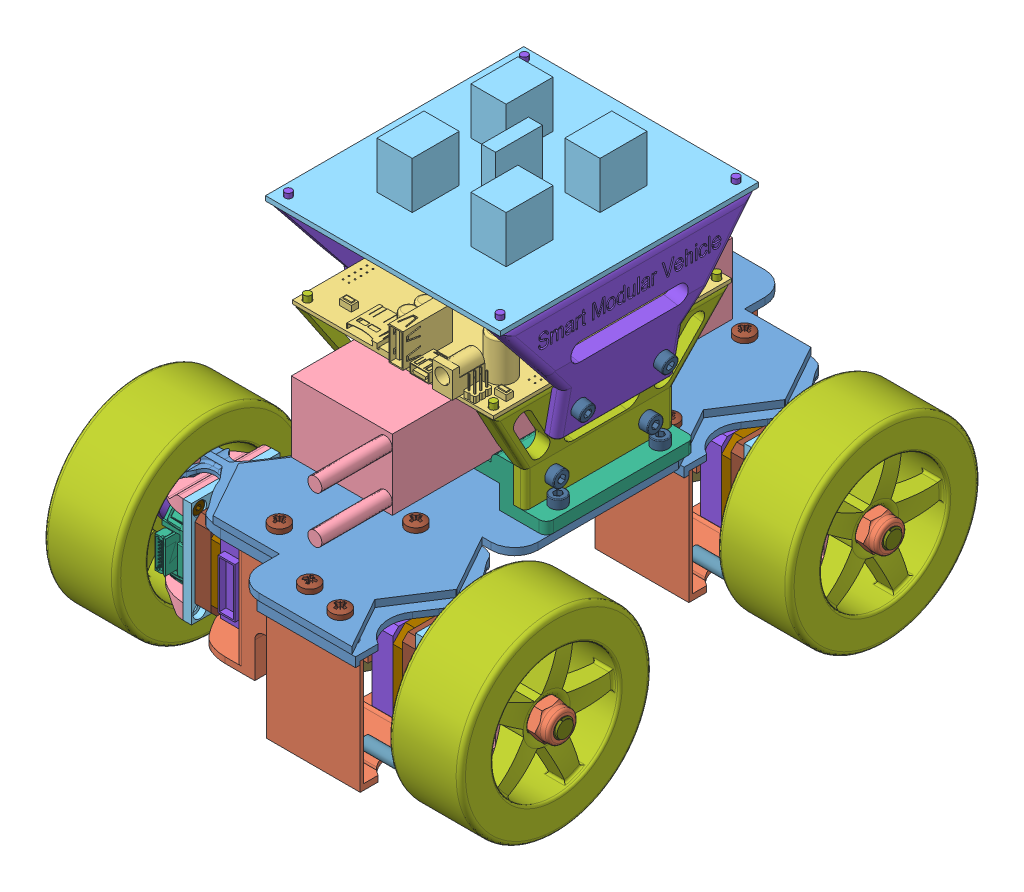
SolidWorks assembly Test chassis, configuration Default. Lengths in mm.
Overall size (185.37 190.89 245.78).
162 component instances, 31 part files, 60 mates.
Components (placement in the parent):
- Chassis-1: Chassis [Default] at origin size (92.7 3 227)
- Module Assembly-1: Module Assembly [Default] at (-66.5 -27.5 -66.5) x (0 0 1) z (-1 0 0) size (105.78 105.78 97.81)
  - Housing-1: Housing [Default] at origin size (64.25 48.5 67.91)
  - Lager 12x8-1: Lager 12x8 [Default] at (0 -18.25 0.75) x (-0.914388 0 0.40484) z (-0.40484 0 -0.914388) size (12 3.5 12)
  - Fusee-1: Fusee [Default] at (0 2 0.75) size (49.04 45 20.5)
  - Fusee base-1: Fusee base [Default] at (0 2 -15.25) x (-1 0 0) z (0 -1 0) size (37.62 3.5 44.8)
  - amt112s-v-1: amt112s-v [Défaut] at (0 2 -12.48) x (0 1 0) z (0 0 1) size (28.68 37.25 10.4)
  - Wheel-1: Wheel [Default] at (0 2 -8.55) x (0.929787 0.368098 0) z (0.368098 -0.929787 0) size (81.5 31 81.5)
  - Ensamblaje_Nema14-1: Ensamblaje_Nema14 [Predeterminado] at (4.764 -15.5 -30.1157) x (-1 0 0) z (0 1 0) size (37.8 40 35)
    - nema14_base-1: nema14_base [Predeterminado] at (-12.736 -8.6343 35) size (37.8 9 35)
    - nema14_centro-1: nema14_centro [Predeterminado] at (-12.736 0.3657 35) size (35 4 35)
    - nema14_eje-1: nema14_eje [Predeterminado] at (4.764 -6.6343 17.5) x (0 1 0) z (-0.939004 0 0.343907) size (38 5 5)
    - nema14_techo-1: nema14_techo [Predeterminado] at (-12.736 4.3657 35) size (35 9 35)
  - TowerPro-SG90-Montaj-1: TowerPro-SG90-Montaj [Default] at (-25.7048 26.288 -66.0832) x (0 0 1) z (1 0 0) size (11.5 29.2 32.5) (flexible)
    - TowerPro-SG90-Body-1: TowerPro-SG90-Body [Default] at (13.6721 7.288 30.7048) size (11.5 26 32.5) (hidden)
    - ServoFinalGear-1: ServoFinalGear [Default] at (13.6721 33.288 25.7048) x (0.607544 0 -0.794286) z (0.794286 0 0.607544) size (4.64 3.2 4.64) (hidden)
  - Servo control dual control horn-1: Servo control dual control horn [Default] at (0 -7.5 -52.4111) x (0.891007 0 0.45399) z (0.45399 0 -0.891007) size (37.9 4.5 7.8)
  - Ball joint assy-1: Ball joint assy [Default] at (-26.7302 -5 -12.8697) x (-0.874356 0 0.485286) z (0.485286 0 0.874356) size (15.43 16.21 22.24) (flexible)
    - Ball-1: Ball [Default] at origin size (5.5 15.11 5.5)
    - Joint-1: Joint [Default] at (-3.8823 13.66 -6.9948) x (0.874356 0 -0.485286) z (0 -1 0) size (5.1 22.6 5.1)
  - Ball joint assy-2: Ball joint assy [Default] at (-26.7302 -5 -66.0308) x (-0.846813 0 0.531891) z (0.531891 0 0.846813) size (16.34 16.21 21.85) (flexible)
    - Ball-1: Ball [Default] at origin size (5.5 15.11 5.5)
    - Joint-1: Joint [Default] at (4.2551 13.66 6.7745) x (-0.846813 0 0.531891) z (0 -1 0) size (5.1 22.6 5.1)
  - Steering rod-1: Steering rod [Default] at (-26.7302 -18.66 -18.4608) x (-0.014502 0.999895 0) z (-0.999895 -0.014502 0) size (3 28.27 3)
  - Wheel adapter-1: Wheel adapter [Default] at (0 2 -13.8175) x (0.291296 -0.956633 0) z (-0.956633 -0.291296 0) size (8.34 40 8.37)
  - Wheel spacer-1: Wheel spacer [Default] at (0 2 12.25) x (0.368098 -0.929787 0) z (0.929787 0.368098 0) size (13.86 8 12)
  - screw_din_7984-m3x5-8_8-1: screw_din_7984-m3x5-8_8 [Default] at (15.31 20.9 -16.25) x (0.933505 0.358563 0) z (0 0 -1) size (5.5 5.5 7)
  - Housing lid-1: Housing lid [Default] at (0 4 0) x (-1 0 0) z (0 0 1) size (68.25 9.28 69.91)
  - Lager 12x8-3: Lager 12x8 [Default] at (0 22.25 0.75) x (-0.914388 0 0.40484) z (0.40484 0 0.914388) size (12 3.5 12) (hidden)
  - M8 nut-1: M8 nut [Default] at (0 2 16.6825) x (-0.817347 -0.576146 0) z (0 0 1) size (13 16.06 8.5)
  - screw_din_7984-m3x5-8_8-2: screw_din_7984-m3x5-8_8 [Default] at (15.31 -16.9 -16.25) x (-0.933505 0.358563 0) z (0 0 -1) size (5.5 5.5 7) (hidden)
  - screw_din_7984-m3x5-8_8-3: screw_din_7984-m3x5-8_8 [Default] at (-15.31 20.9 -16.25) x (0.933505 -0.358563 0) z (0 0 -1) size (5.5 5.5 7) (hidden)
  - screw_din_7984-m3x5-8_8-4: screw_din_7984-m3x5-8_8 [Default] at (-15.31 -16.9 -16.25) x (-0.933505 -0.358563 0) z (0 0 -1) size (5.5 5.5 7) (hidden)
- Module Assembly-3: Module Assembly [Default] at (66.5 -27.5 -66.5) x (0 0 -1) z (1 0 0) size (105.78 105.78 97.81)
  - Housing-1: Housing [Default] at origin size (64.25 48.5 67.91)
  - Lager 12x8-1: Lager 12x8 [Default] at (0 -18.25 0.75) x (-0.914388 0 0.40484) z (-0.40484 0 -0.914388) size (12 3.5 12)
  - Fusee-1: Fusee [Default] at (0 2 0.75) size (49.04 45 20.5)
  - Fusee base-1: Fusee base [Default] at (0 2 -15.25) x (-1 0 0) z (0 -1 0) size (37.62 3.5 44.8)
  - amt112s-v-1: amt112s-v [Défaut] at (0 2 -12.48) x (0 1 0) z (0 0 1) size (28.68 37.25 10.4)
  - Wheel-1: Wheel [Default] at (0 2 -8.55) x (0.929787 0.368098 0) z (0.368098 -0.929787 0) size (81.5 31 81.5)
  - Ensamblaje_Nema14-1: Ensamblaje_Nema14 [Predeterminado] at (4.764 -15.5 -30.1157) x (-1 0 0) z (0 1 0) size (37.8 40 35)
    - nema14_base-1: nema14_base [Predeterminado] at (-12.736 -8.6343 35) size (37.8 9 35)
    - nema14_centro-1: nema14_centro [Predeterminado] at (-12.736 0.3657 35) size (35 4 35)
    - nema14_eje-1: nema14_eje [Predeterminado] at (4.764 -6.6343 17.5) x (0 1 0) z (-0.939004 0 0.343907) size (38 5 5)
    - nema14_techo-1: nema14_techo [Predeterminado] at (-12.736 4.3657 35) size (35 9 35)
  - TowerPro-SG90-Montaj-1: TowerPro-SG90-Montaj [Default] at (-25.7048 26.288 -66.0832) x (0 0 1) z (1 0 0) size (11.5 29.2 32.5) (flexible)
    - TowerPro-SG90-Body-1: TowerPro-SG90-Body [Default] at (13.6721 7.288 30.7048) size (11.5 26 32.5) (hidden)
    - ServoFinalGear-1: ServoFinalGear [Default] at (13.6721 33.288 25.7048) x (0.607544 0 -0.794286) z (0.794286 0 0.607544) size (4.64 3.2 4.64) (hidden)
  - Servo control dual control horn-1: Servo control dual control horn [Default] at (0 -7.5 -52.4111) x (0.891007 0 0.45399) z (0.45399 0 -0.891007) size (37.9 4.5 7.8)
  - Ball joint assy-1: Ball joint assy [Default] at (-26.7302 -5 -12.8697) x (-0.874356 0 0.485286) z (0.485286 0 0.874356) size (15.43 16.21 22.24) (flexible)
    - Ball-1: Ball [Default] at origin size (5.5 15.11 5.5)
    - Joint-1: Joint [Default] at (-3.8823 13.66 -6.9948) x (0.874356 0 -0.485286) z (0 -1 0) size (5.1 22.6 5.1)
  - Ball joint assy-2: Ball joint assy [Default] at (-26.7302 -5 -66.0308) x (-0.846813 0 0.531891) z (0.531891 0 0.846813) size (16.34 16.21 21.85) (flexible)
    - Ball-1: Ball [Default] at origin size (5.5 15.11 5.5)
    - Joint-1: Joint [Default] at (4.2551 13.66 6.7745) x (-0.846813 0 0.531891) z (0 -1 0) size (5.1 22.6 5.1)
  - Steering rod-1: Steering rod [Default] at (-26.7302 -18.66 -18.4608) x (-0.014502 0.999895 0) z (-0.999895 -0.014502 0) size (3 28.27 3)
  - Wheel adapter-1: Wheel adapter [Default] at (0 2 -13.8175) x (0.291296 -0.956633 0) z (-0.956633 -0.291296 0) size (8.34 40 8.37)
  - Wheel spacer-1: Wheel spacer [Default] at (0 2 12.25) x (0.368098 -0.929787 0) z (0.929787 0.368098 0) size (13.86 8 12)
  - screw_din_7984-m3x5-8_8-1: screw_din_7984-m3x5-8_8 [Default] at (15.31 20.9 -16.25) x (0.933505 0.358563 0) z (0 0 -1) size (5.5 5.5 7)
  - Housing lid-1: Housing lid [Default] at (0 4 0) x (-1 0 0) z (0 0 1) size (68.25 9.28 69.91)
  - Lager 12x8-3: Lager 12x8 [Default] at (0 22.25 0.75) x (-0.914388 0 0.40484) z (0.40484 0 0.914388) size (12 3.5 12) (hidden)
  - M8 nut-1: M8 nut [Default] at (0 2 16.6825) x (-0.817347 -0.576146 0) z (0 0 1) size (13 16.06 8.5)
  - screw_din_7984-m3x5-8_8-2: screw_din_7984-m3x5-8_8 [Default] at (15.31 -16.9 -16.25) x (-0.933505 0.358563 0) z (0 0 -1) size (5.5 5.5 7) (hidden)
  - screw_din_7984-m3x5-8_8-3: screw_din_7984-m3x5-8_8 [Default] at (-15.31 20.9 -16.25) x (0.933505 -0.358563 0) z (0 0 -1) size (5.5 5.5 7) (hidden)
  - screw_din_7984-m3x5-8_8-4: screw_din_7984-m3x5-8_8 [Default] at (-15.31 -16.9 -16.25) x (-0.933505 -0.358563 0) z (0 0 -1) size (5.5 5.5 7) (hidden)
- Module Assembly-6: Module Assembly [Default] at (-66.5 -27.5 73.5) x (0 0 1) z (-1 0 0) size (105.78 105.78 97.81)
  - Housing-1: Housing [Default] at origin size (64.25 48.5 67.91)
  - Lager 12x8-1: Lager 12x8 [Default] at (0 -18.25 0.75) x (-0.914388 0 0.40484) z (-0.40484 0 -0.914388) size (12 3.5 12)
  - Fusee-1: Fusee [Default] at (0 2 0.75) size (49.04 45 20.5)
  - Fusee base-1: Fusee base [Default] at (0 2 -15.25) x (-1 0 0) z (0 -1 0) size (37.62 3.5 44.8)
  - amt112s-v-1: amt112s-v [Défaut] at (0 2 -12.48) x (0 1 0) z (0 0 1) size (28.68 37.25 10.4)
  - Wheel-1: Wheel [Default] at (0 2 -8.55) x (0.929787 0.368098 0) z (0.368098 -0.929787 0) size (81.5 31 81.5)
  - Ensamblaje_Nema14-1: Ensamblaje_Nema14 [Predeterminado] at (4.764 -15.5 -30.1157) x (-1 0 0) z (0 1 0) size (37.8 40 35)
    - nema14_base-1: nema14_base [Predeterminado] at (-12.736 -8.6343 35) size (37.8 9 35)
    - nema14_centro-1: nema14_centro [Predeterminado] at (-12.736 0.3657 35) size (35 4 35)
    - nema14_eje-1: nema14_eje [Predeterminado] at (4.764 -6.6343 17.5) x (0 1 0) z (-0.939004 0 0.343907) size (38 5 5)
    - nema14_techo-1: nema14_techo [Predeterminado] at (-12.736 4.3657 35) size (35 9 35)
  - TowerPro-SG90-Montaj-1: TowerPro-SG90-Montaj [Default] at (-25.7048 26.288 -66.0832) x (0 0 1) z (1 0 0) size (11.5 29.2 32.5) (flexible)
    - TowerPro-SG90-Body-1: TowerPro-SG90-Body [Default] at (13.6721 7.288 30.7048) size (11.5 26 32.5) (hidden)
    - ServoFinalGear-1: ServoFinalGear [Default] at (13.6721 33.288 25.7048) x (0.607544 0 -0.794286) z (0.794286 0 0.607544) size (4.64 3.2 4.64) (hidden)
  - Servo control dual control horn-1: Servo control dual control horn [Default] at (0 -7.5 -52.4111) x (0.891007 0 0.45399) z (0.45399 0 -0.891007) size (37.9 4.5 7.8)
  - Ball joint assy-1: Ball joint assy [Default] at (-26.7302 -5 -12.8697) x (-0.874356 0 0.485286) z (0.485286 0 0.874356) size (15.43 16.21 22.24) (flexible)
    - Ball-1: Ball [Default] at origin size (5.5 15.11 5.5)
    - Joint-1: Joint [Default] at (-3.8823 13.66 -6.9948) x (0.874356 0 -0.485286) z (0 -1 0) size (5.1 22.6 5.1)
  - Ball joint assy-2: Ball joint assy [Default] at (-26.7302 -5 -66.0308) x (-0.846813 0 0.531891) z (0.531891 0 0.846813) size (16.34 16.21 21.85) (flexible)
    - Ball-1: Ball [Default] at origin size (5.5 15.11 5.5)
    - Joint-1: Joint [Default] at (4.2551 13.66 6.7745) x (-0.846813 0 0.531891) z (0 -1 0) size (5.1 22.6 5.1)
  - Steering rod-1: Steering rod [Default] at (-26.7302 -18.66 -18.4608) x (-0.014502 0.999895 0) z (-0.999895 -0.014502 0) size (3 28.27 3)
  - Wheel adapter-1: Wheel adapter [Default] at (0 2 -13.8175) x (0.291296 -0.956633 0) z (-0.956633 -0.291296 0) size (8.34 40 8.37)
  - Wheel spacer-1: Wheel spacer [Default] at (0 2 12.25) x (0.368098 -0.929787 0) z (0.929787 0.368098 0) size (13.86 8 12)
  - screw_din_7984-m3x5-8_8-1: screw_din_7984-m3x5-8_8 [Default] at (15.31 20.9 -16.25) x (0.933505 0.358563 0) z (0 0 -1) size (5.5 5.5 7)
  - Housing lid-1: Housing lid [Default] at (0 4 0) x (-1 0 0) z (0 0 1) size (68.25 9.28 69.91)
  - Lager 12x8-3: Lager 12x8 [Default] at (0 22.25 0.75) x (-0.914388 0 0.40484) z (0.40484 0 0.914388) size (12 3.5 12) (hidden)
  - M8 nut-1: M8 nut [Default] at (0 2 16.6825) x (-0.817347 -0.576146 0) z (0 0 1) size (13 16.06 8.5)
  - screw_din_7984-m3x5-8_8-2: screw_din_7984-m3x5-8_8 [Default] at (15.31 -16.9 -16.25) x (-0.933505 0.358563 0) z (0 0 -1) size (5.5 5.5 7) (hidden)
  - screw_din_7984-m3x5-8_8-3: screw_din_7984-m3x5-8_8 [Default] at (-15.31 20.9 -16.25) x (0.933505 -0.358563 0) z (0 0 -1) size (5.5 5.5 7) (hidden)
  - screw_din_7984-m3x5-8_8-4: screw_din_7984-m3x5-8_8 [Default] at (-15.31 -16.9 -16.25) x (-0.933505 -0.358563 0) z (0 0 -1) size (5.5 5.5 7) (hidden)
- Module Assembly-7: Module Assembly [Default] at (66.5 -27.5 73.5) x (0 0 -1) z (1 0 0) size (105.78 105.78 97.81)
  - Housing-1: Housing [Default] at origin size (64.25 48.5 67.91)
  - Lager 12x8-1: Lager 12x8 [Default] at (0 -18.25 0.75) x (-0.914388 0 0.40484) z (-0.40484 0 -0.914388) size (12 3.5 12)
  - Fusee-1: Fusee [Default] at (0 2 0.75) size (49.04 45 20.5)
  - Fusee base-1: Fusee base [Default] at (0 2 -15.25) x (-1 0 0) z (0 -1 0) size (37.62 3.5 44.8)
  - amt112s-v-1: amt112s-v [Défaut] at (0 2 -12.48) x (0 1 0) z (0 0 1) size (28.68 37.25 10.4)
  - Wheel-1: Wheel [Default] at (0 2 -8.55) x (0.929787 0.368098 0) z (0.368098 -0.929787 0) size (81.5 31 81.5)
  - Ensamblaje_Nema14-1: Ensamblaje_Nema14 [Predeterminado] at (4.764 -15.5 -30.1157) x (-1 0 0) z (0 1 0) size (37.8 40 35)
    - nema14_base-1: nema14_base [Predeterminado] at (-12.736 -8.6343 35) size (37.8 9 35)
    - nema14_centro-1: nema14_centro [Predeterminado] at (-12.736 0.3657 35) size (35 4 35)
    - nema14_eje-1: nema14_eje [Predeterminado] at (4.764 -6.6343 17.5) x (0 1 0) z (-0.939004 0 0.343907) size (38 5 5)
    - nema14_techo-1: nema14_techo [Predeterminado] at (-12.736 4.3657 35) size (35 9 35)
  - TowerPro-SG90-Montaj-1: TowerPro-SG90-Montaj [Default] at (-25.7048 26.288 -66.0832) x (0 0 1) z (1 0 0) size (11.5 29.2 32.5) (flexible)
    - TowerPro-SG90-Body-1: TowerPro-SG90-Body [Default] at (13.6721 7.288 30.7048) size (11.5 26 32.5) (hidden)
    - ServoFinalGear-1: ServoFinalGear [Default] at (13.6721 33.288 25.7048) x (0.607544 0 -0.794286) z (0.794286 0 0.607544) size (4.64 3.2 4.64) (hidden)
  - Servo control dual control horn-1: Servo control dual control horn [Default] at (0 -7.5 -52.4111) x (0.891007 0 0.45399) z (0.45399 0 -0.891007) size (37.9 4.5 7.8)
  - Ball joint assy-1: Ball joint assy [Default] at (-26.7302 -5 -12.8697) x (-0.874356 0 0.485286) z (0.485286 0 0.874356) size (15.43 16.21 22.24) (flexible)
    - Ball-1: Ball [Default] at origin size (5.5 15.11 5.5)
    - Joint-1: Joint [Default] at (-3.8823 13.66 -6.9948) x (0.874356 0 -0.485286) z (0 -1 0) size (5.1 22.6 5.1)
  - Ball joint assy-2: Ball joint assy [Default] at (-26.7302 -5 -66.0308) x (-0.846813 0 0.531891) z (0.531891 0 0.846813) size (16.34 16.21 21.85) (flexible)
    - Ball-1: Ball [Default] at origin size (5.5 15.11 5.5)
    - Joint-1: Joint [Default] at (4.2551 13.66 6.7745) x (-0.846813 0 0.531891) z (0 -1 0) size (5.1 22.6 5.1)
  - Steering rod-1: Steering rod [Default] at (-26.7302 -18.66 -18.4608) x (-0.014502 0.999895 0) z (-0.999895 -0.014502 0) size (3 28.27 3)
  - Wheel adapter-1: Wheel adapter [Default] at (0 2 -13.8175) x (0.291296 -0.956633 0) z (-0.956633 -0.291296 0) size (8.34 40 8.37)
  - Wheel spacer-1: Wheel spacer [Default] at (0 2 12.25) x (0.368098 -0.929787 0) z (0.929787 0.368098 0) size (13.86 8 12)
  - screw_din_7984-m3x5-8_8-1: screw_din_7984-m3x5-8_8 [Default] at (15.31 20.9 -16.25) x (0.933505 0.358563 0) z (0 0 -1) size (5.5 5.5 7)
  - Housing lid-1: Housing lid [Default] at (0 4 0) x (-1 0 0) z (0 0 1) size (68.25 9.28 69.91)
  - Lager 12x8-3: Lager 12x8 [Default] at (0 22.25 0.75) x (-0.914388 0 0.40484) z (0.40484 0 0.914388) size (12 3.5 12) (hidden)
  - M8 nut-1: M8 nut [Default] at (0 2 16.6825) x (-0.817347 -0.576146 0) z (0 0 1) size (13 16.06 8.5)
  - screw_din_7984-m3x5-8_8-2: screw_din_7984-m3x5-8_8 [Default] at (15.31 -16.9 -16.25) x (-0.933505 0.358563 0) z (0 0 -1) size (5.5 5.5 7) (hidden)
  - screw_din_7984-m3x5-8_8-3: screw_din_7984-m3x5-8_8 [Default] at (-15.31 20.9 -16.25) x (0.933505 -0.358563 0) z (0 0 -1) size (5.5 5.5 7) (hidden)
  - screw_din_7984-m3x5-8_8-4: screw_din_7984-m3x5-8_8 [Default] at (-15.31 -16.9 -16.25) x (-0.933505 -0.358563 0) z (0 0 -1) size (5.5 5.5 7) (hidden)
- Olimex_SMT32-E407-1: Olimex_SMT32-E407 [Défaut] at (42.8 54 54.25) x (0 0 -1) z (1 0 0) size (104.5 18.7 85.6)
- Battery-1: Battery [Default] at (0 19 3.5) x (0 0 1) z (-1 0 0) size (175 30 43)
- PCB-1: PCB [Default] at (0 90.5 3.5) size (100 22 110)
- Battery holder-1: Battery holder [Default] at (0 3 3.5) x (1 0 0) z (0 1 0) size (92.7 63.5 20)
- Olimex holder-1: Olimex holder [Default] at (-32.35 3 3.5) x (0 1 0) z (-1 0 0) size (50 102 10.07)
- PCB holder-1: PCB holder [Default] at (-50 90.5 3.4069) x (0 0 1) z (-1 0 0) size (110 60.5 10.59)
- Olimex holder-2: Olimex holder [Default] at (32.35 3 3.5) x (0 1 0) z (1 0 0) size (50 102 10.07)
- PCB holder-4: PCB holder [Default] at (50 90.5 3.4069) x (0 0 -1) z (1 0 0) size (110 60.5 10.59)
- Olimex holder-3: Olimex holder [Default] at (32.35 3 3.5) x (0 1 0) z (1 0 0) size (50 102 10.07)
- wasi_stainless_steel_a4_din_912_m4x16-1: wasi_stainless_steel_a4_din_912_m4x16 [Default] at (-46.1186 44 -14.2848) x (0.984895 0.173151 0) z (0 0 1) size (19.82 6.78 6.78)
- wasi_stainless_steel_a4_din_912_m4x6-1: wasi_stainless_steel_a4_din_912_m4x6 [Default] at (-46.1186 44 21.0986) x (0.984895 0.173151 0) z (0 0 1) size (9.82 6.78 6.78)
- wasi_stainless_steel_a4_din_912_m4x6-2: wasi_stainless_steel_a4_din_912_m4x6 [Default] at (-37.35 16 -16.5) size (9.82 6.78 6.78)
- wasi_stainless_steel_a4_din_912_m4x6-3: wasi_stainless_steel_a4_din_912_m4x6 [Default] at (-37.35 16 23.5) size (9.82 6.78 6.78)
- wasi_stainless_steel_a4_din_912_m4x6-5: wasi_stainless_steel_a4_din_912_m4x6 [Default] at (-41.35 8 25.25) x (0 -1 0) z (0.081703 0 0.996657) size (9.82 6.78 6.78)
- wasi_stainless_steel_a4_din_912_m4x6-6: wasi_stainless_steel_a4_din_912_m4x6 [Default] at (-41.35 8 -18.25) x (0 -1 0) z (-0.546944 0 0.837169) size (9.82 6.78 6.78)
- wasi_stainless_steel_a4_din_912_m4x6-7: wasi_stainless_steel_a4_din_912_m4x6 [Default] at (46.1186 44 21.0986) x (-0.984895 0.173151 0) z (-0.169211 -0.962484 0.212114) size (9.82 6.78 6.78)
- wasi_stainless_steel_a4_din_912_m4x6-8: wasi_stainless_steel_a4_din_912_m4x6 [Default] at (37.35 16 23.5) x (-1 0 0) z (0 -0.924225 -0.381849) size (9.82 6.78 6.78)
- wasi_stainless_steel_a4_din_912_m4x6-9: wasi_stainless_steel_a4_din_912_m4x6 [Default] at (41.35 8 25.25) x (0 -1 0) z (-0.546944 0 0.837169) size (9.82 6.78 6.78)
- m4x10-1: m4x10 [Default] at (14.3389 3 -81.25) x (0 -1 0) z (0 0 1) size (14.78 13.48 13.28)
- m4x10-2: m4x10 [Default] at (30.3389 3 -33) x (0 -1 0) z (0 0 1) size (14.78 13.48 13.28)
- m4x10-3: m4x10 [Default] at (14.3389 3 -36) x (0 -1 0) z (0.456017 0 0.889971) size (14.78 13.48 13.28)
- m4x10-7: m4x10 [Default] at (-14.3389 3 -97) x (0 -1 0) z (0 0 1) size (14.78 13.48 13.28)
- m4x10-8: m4x10 [Default] at (-30.3389 3 -100) x (0 -1 0) z (0 0 1) size (14.78 13.48 13.28)
- m4x10-9: m4x10 [Default] at (-14.3389 3 -51.75) x (0 -1 0) z (-0.064728 0 0.997903) size (14.78 13.48 13.28)
- wasi_stainless_steel_a4_din_912_m4x6-10: wasi_stainless_steel_a4_din_912_m4x6 [Default] at (46.1186 44 -14.0986) x (-0.984895 0.173151 0) z (0.169211 0.962484 0.212114) size (9.82 6.78 6.78)
- wasi_stainless_steel_a4_din_912_m4x6-11: wasi_stainless_steel_a4_din_912_m4x6 [Default] at (37.35 16 -16.5) x (-1 0 0) z (0 0.924225 -0.381849) size (9.82 6.78 6.78)
- wasi_stainless_steel_a4_din_912_m4x6-12: wasi_stainless_steel_a4_din_912_m4x6 [Default] at (41.35 8 -18.25) x (0 -1 0) z (0.546944 0 0.837169) size (9.82 6.78 6.78)
- m4x10-4: m4x10 [Default] at (14.3389 3 58.75) x (0 -1 0) z (0 0 1) size (14.78 13.48 13.28)
- m4x10-5: m4x10 [Default] at (14.3389 3 104) x (0 -1 0) z (0.456017 0 0.889971) size (14.78 13.48 13.28)
- m4x10-6: m4x10 [Default] at (30.3389 3 107) x (0 -1 0) z (0 0 1) size (14.78 13.48 13.28)
- m4x10-10: m4x10 [Default] at (-30.3389 3 40) x (0 -1 0) z (0 0 1) size (14.78 13.48 13.28)
- m4x10-11: m4x10 [Default] at (-14.3389 3 43) x (0 -1 0) z (0 0 1) size (14.78 13.48 13.28)
- m4x10-12: m4x10 [Default] at (-14.3389 3 88.25) x (0 -1 0) z (-0.064728 0 0.997903) size (14.78 13.48 13.28)
Mates (geometry in assembly coordinates):
- Parallel1: parallel anti-aligned: plane of Chassis-1 through (-46.35 3 117) normal (-1 0 0); plane of Module Assembly-1/Housing-1 through (-6.8389 -48.5 -25) normal (1 0 0)
- Coincident3: coincident anti-aligned: plane of Chassis-1 through (0 0 0) normal (0 -1 0); plane of Module Assembly-1/Housing lid-1 through (-66.5 0 -66.5) normal (0 1 0)
- Coincident4: coincident aligned: plane of Chassis-1 through (-46.35 3 -110) normal (0 0 -1); plane of Module Assembly-1/Housing lid-1 through (-66.5 -4 -110) normal (0 0 -1)
- Parallel3: parallel anti-aligned: plane of Chassis-1 through (46.35 3 117) normal (1 0 0); plane of Module Assembly-3/Housing lid-1 through (4.8389 -4 -66.5) normal (-1 0 0)
- Coincident6: coincident anti-aligned: plane of Chassis-1 through (0 0 0) normal (0 -1 0); plane of Module Assembly-3/Housing lid-1 through (66.5 0 -66.5) normal (0 1 0)
- Distance2: distance = 66.5 mm anti-aligned: plane of assembly through (0 0 0) normal (1 0 0); plane of Module Assembly-1/Housing-1 through (-66.5 -27.5 -66.5) normal (-1 0 0)
- Distance3: distance = 66.5 mm aligned: plane of assembly through (0 0 0) normal (1 0 0); plane of Module Assembly-3/Housing-1 through (66.5 -27.5 -66.5) normal (1 0 0)
- Coincident11: coincident anti-aligned: plane of Module Assembly-1/Housing-1 through (-66.5 -27.5 -66.5) normal (0 0 1); plane of Module Assembly-3/Housing-1 through (66.5 -27.5 -66.5) normal (0 0 -1)
- Parallel4: parallel anti-aligned: plane of Chassis-1 through (46.35 3 117) normal (1 0 0); plane of Olimex_SMT32-E407-1 through (-42.8 188.2765 54.25) normal (-1 0 0)
- Parallel5: parallel aligned: plane of Chassis-1 through (-46.35 3 117) normal (-1 0 0); plane of Battery-1 through (-21.5 49 -69) normal (-1 0 0)
- Coincident18: coincident anti-aligned: plane of Battery-1 through (0 19 3.5) normal (0 -1 0); plane of Battery holder-1 through (500000 19 35.25) normal (0 1 0)
- Coincident14: coincident anti-aligned: plane of Chassis-1 through (0 0 0) normal (1 0 0); plane of Battery-1 through (0 19 3.5) normal (-1 0 0)
- Coincident19: coincident anti-aligned: plane of Chassis-1 through (0 0 3.5) normal (0 0 1); plane of Battery holder-1 through (0 3 3.5) normal (0 0 -1)
- Coincident21: coincident aligned: plane of Chassis-1 through (-46.35 3 117) normal (-1 0 0); plane of Battery holder-1 through (-46.35 8 -28.25) normal (-1 0 0)
- Coincident22: coincident aligned: plane of Chassis-1 through (-46.35 3 117) normal (-1 0 0); plane of Battery holder-1 through (-46.35 8 -28.25) normal (-1 0 0)
- Coincident23: coincident anti-aligned: plane of Chassis-1 through (0 3 0) normal (0 1 0); plane of Battery holder-1 through (0 3 3.5) normal (0 -1 0)
- Coincident24: coincident anti-aligned: plane of Battery-1 through (0 19 3.5) normal (0 0 1); plane of Battery holder-1 through (0 3 3.5) normal (0 0 -1)
- Coincident25: coincident anti-aligned: plane of Olimex_SMT32-E407-1 through (42.8 54 3.5) normal (0 0 1); plane of Olimex holder-1 through (-32.35 3 3.5) normal (0 0 -1)
- Coincident26: coincident anti-aligned: plane of Olimex_SMT32-E407-1 through (0 54 54.25) normal (-1 0 0); plane of Battery holder-1 through (0 3 3.5) normal (1 0 0)
- Distance5: distance = 5 mm anti-aligned: plane of Battery-1 through (0 49 3.5) normal (0 1 0); plane of Olimex_SMT32-E407-1 through (42.8 54 54.25) normal (0 -1 0)
- Coincident32: coincident aligned: plane of PCB-1 through (0 90.5 3.5) normal (1 0 0); plane of assembly through (0 0 0) normal (1 0 0)
- Coincident34: coincident anti-aligned: plane of PCB-1 through (0 90.5 3.5) normal (0 0 1); plane of Olimex holder-1 through (-32.35 3 3.5) normal (0 0 -1)
- Distance6: distance = 35 mm anti-aligned: plane of Olimex_SMT32-E407-1 through (42.8 55.5 54.25) normal (0 1 0); plane of PCB-1 through (0 90.5 3.5) normal (0 -1 0)
- Coincident44: coincident anti-aligned: plane of PCB-1 through (0 90.5 3.5) normal (0 -1 0); plane of PCB holder-1 through (-43.5 90.5 -51.5931) normal (0 1 0)
- Coincident45: coincident aligned: plane of PCB-1 through (-50 92.5 58.5) normal (-1 0 0); plane of PCB holder-1 through (-50 90.5 3.4069) normal (-1 0 0)
- Coincident46: coincident anti-aligned: plane of Battery holder-1 through (-32.35 23 -28.25) normal (-1 0 0); plane of Olimex holder-1 through (-32.35 3 3.5) normal (1 0 0)
- Coincident47: coincident anti-aligned: plane of Battery holder-1 through (0 8 3.5) normal (0 1 0); plane of Olimex holder-1 through (-44.35 8 35.25) normal (0 -1 0)
- Concentric4: concentric anti-aligned: circle of Olimex_SMT32-E407-1; cylinder of Olimex holder-1 through (-39.6 58 -44.05) axis (0 -1 0) radius 1.5
- Concentric5: concentric aligned: cylinder of PCB-1 through (-45 92.5 -46.75) axis (0 -1 0) radius 1.25; cylinder of PCB holder-1 through (-45 94.5 -46.75) axis (0 -1 0) radius 1.5
- Concentric6: concentric aligned: cylinder of Battery holder-1 through (-17.35 16 -16.5) axis (-1 0 0) radius 2; cylinder of Olimex holder-1 through (-32.35 16 -16.5) axis (-1 0 0) radius 2.25
- Concentric7: concentric aligned: circle of PCB holder-1; cylinder of wasi_stainless_steel_a4_din_912_m4x16-1 through (-46.1186 44 -14.2848) axis (-0.984895 -0.173151 0) radius 2
- Coincident48: coincident aligned: plane of PCB holder-1 through (-47.8767 54 -51.5931) normal (-0.984895 -0.173151 0); circle of wasi_stainless_steel_a4_din_912_m4x16-1
- Concentric57: concentric aligned: cylinder of PCB holder-1 through (-30.9994 46.6581 21.0986) axis (-0.984895 -0.173151 0) radius 2.25; cylinder of wasi_stainless_steel_a4_din_912_m4x6-1 through (-46.1186 44 21.0986) axis (-0.984895 -0.173151 0) radius 2
- Coincident98: coincident anti-aligned: plane of PCB holder-1 through (-47.8767 54 -51.5931) normal (-0.984895 -0.173151 0); plane of wasi_stainless_steel_a4_din_912_m4x6-1 through (-46.1186 44 21.0986) normal (0.984895 0.173151 0)
- Concentric58: concentric aligned: cylinder of Olimex holder-1 through (-32.35 16 -16.5) axis (-1 0 0) radius 2.25; cylinder of wasi_stainless_steel_a4_din_912_m4x6-2 through (-37.35 16 -16.5) axis (-1 0 0) radius 2
- Coincident99: coincident aligned: plane of Olimex holder-1 through (-37.35 8 54.5) normal (-1 0 0); circle of wasi_stainless_steel_a4_din_912_m4x6-2
- Concentric59: concentric aligned: cylinder of Olimex holder-1 through (-32.35 16 23.5) axis (-1 0 0) radius 2.25; cylinder of wasi_stainless_steel_a4_din_912_m4x6-3 through (-37.35 16 23.5) axis (-1 0 0) radius 2
- Coincident100: coincident aligned: plane of Olimex holder-1 through (-37.35 8 54.5) normal (-1 0 0); circle of wasi_stainless_steel_a4_din_912_m4x6-3
- Concentric60: concentric aligned: cylinder of Battery holder-1 through (-41.35 3 25.25) axis (0 1 0) radius 2.25; cylinder of wasi_stainless_steel_a4_din_912_m4x6-5 through (-41.35 8 25.25) axis (0 1 0) radius 2
- Coincident101: coincident anti-aligned: plane of Battery holder-1 through (0 8 3.5) normal (0 1 0); plane of wasi_stainless_steel_a4_din_912_m4x6-5 through (-41.35 8 25.25) normal (0 -1 0)
- Concentric61: concentric aligned: cylinder of Battery holder-1 through (-41.35 3 -18.25) axis (0 1 0) radius 2.25; cylinder of wasi_stainless_steel_a4_din_912_m4x6-6 through (-41.35 8 -18.25) axis (0 1 0) radius 2
- Coincident102: coincident aligned: plane of Battery holder-1 through (0 8 3.5) normal (0 1 0); circle of wasi_stainless_steel_a4_din_912_m4x6-6
- Concentric62: concentric aligned: cylinder of PCB holder-4 through (30.9994 46.6581 21.0986) axis (0.984895 -0.173151 0) radius 2.25; cylinder of wasi_stainless_steel_a4_din_912_m4x6-7 through (46.1186 44 21.0986) axis (0.984895 -0.173151 0) radius 2
- Coincident103: coincident aligned: plane of PCB holder-4 through (47.8767 54 58.4069) normal (0.984895 -0.173151 0); circle of wasi_stainless_steel_a4_din_912_m4x6-7
- Concentric63: concentric aligned: cylinder of Olimex holder-2 through (32.35 16 23.5) axis (1 0 0) radius 2.25; cylinder of wasi_stainless_steel_a4_din_912_m4x6-8 through (37.35 16 23.5) axis (1 0 0) radius 2
- Coincident104: coincident aligned: plane of Olimex holder-2 through (37.35 8 -47.5) normal (1 0 0); circle of wasi_stainless_steel_a4_din_912_m4x6-8
- Concentric64: concentric aligned: cylinder of Battery holder-1 through (41.35 3 25.25) axis (0 1 0) radius 2.25; cylinder of wasi_stainless_steel_a4_din_912_m4x6-9 through (41.35 8 25.25) axis (0 1 0) radius 2
- Coincident105: coincident aligned: plane of Battery holder-1 through (0 8 3.5) normal (0 1 0); circle of wasi_stainless_steel_a4_din_912_m4x6-9
- Concentric65: concentric anti-aligned: cylinder of Chassis-1 through (14.3389 3 -81.25) axis (0 -1 0) radius 2; cylinder of m4x10-1 through (14.3389 -2.0481 -81.25) axis (0 1 0) radius 2
- Coincident106: coincident anti-aligned: plane of Chassis-1 through (0 3 0) normal (0 1 0); circle of m4x10-1
- Concentric66: concentric anti-aligned: cylinder of Chassis-1 through (30.3389 3 -33) axis (0 -1 0) radius 2; cylinder of m4x10-2 through (30.3389 -2.0481 -33) axis (0 1 0) radius 2
- Coincident107: coincident anti-aligned: plane of Chassis-1 through (0 3 0) normal (0 1 0); circle of m4x10-2
- Concentric67: concentric anti-aligned: cylinder of Chassis-1 through (14.3389 3 -36) axis (0 -1 0) radius 2; cylinder of m4x10-3 through (14.3389 -2.0481 -36) axis (0 1 0) radius 2
- Coincident108: coincident anti-aligned: plane of Chassis-1 through (0 3 0) normal (0 1 0); circle of m4x10-3
- Concentric68: concentric anti-aligned: cylinder of Chassis-1 through (-14.3389 3 -97) axis (0 -1 0) radius 2; cylinder of m4x10-7 through (-14.3389 -2.0481 -97) axis (0 1 0) radius 2
- Coincident109: coincident anti-aligned: plane of Chassis-1 through (0 3 0) normal (0 1 0); circle of m4x10-7
- Concentric69: concentric anti-aligned: cylinder of Chassis-1 through (-30.3389 3 -100) axis (0 -1 0) radius 2; cylinder of m4x10-8 through (-30.3389 -2.0481 -100) axis (0 1 0) radius 2
- Coincident110: coincident anti-aligned: plane of Chassis-1 through (0 3 0) normal (0 1 0); circle of m4x10-8
- Concentric70: concentric anti-aligned: cylinder of Chassis-1 through (-14.3389 3 -51.75) axis (0 -1 0) radius 2; cylinder of m4x10-9 through (-14.3389 -2.0481 -51.75) axis (0 1 0) radius 2
- Coincident111: coincident anti-aligned: plane of Chassis-1 through (0 3 0) normal (0 1 0); circle of m4x10-9
